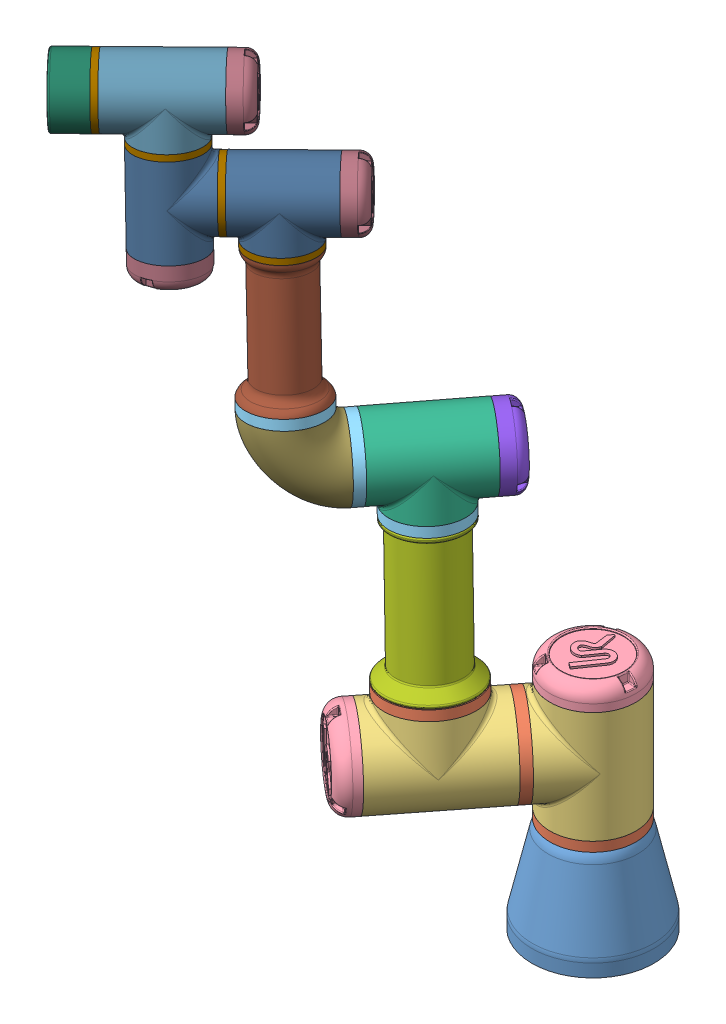
SolidWorks assembly UR3_Assembly, configuration Default. Lengths in mm.
Overall size (416.62 772.65 384.33).
31 component instances, 15 part files, 8 mates.
Components (placement in the parent):
- Base^UR3_Assembly-1: Base^UR3_Assembly [Default] at (189.025 -183.6761 -10.6435) size (133.33 250.8 135.05) (virtual)
  - Base Joint-1: Base Joint [Default] at (46.7051 9.5176 101.7932) size (128 105.8 128)
  - size 2 flange-1: size 2 flange [Default] at (46.7051 110.3176 101.7932) x (0.037243 0 -0.999306) z (0.999306 0 0.037243) size (90 10 90)
  - shoulder - base  1-1: shoulder - base  1 [Default] at (46.7051 115.3176 101.7932) x (-0.616294 0 0.787516) z (-0.787516 0 -0.616294) size (100 122 90)
  - Size 2 Cap-1: Size 2 Cap [Default] at (46.7051 237.3176 101.7932) x (-0.821952 0 -0.569557) z (0.569557 0 -0.821952) size (90 23 90)
- Arm1^UR3_Assembly-1: Arm1^UR3_Assembly [Default] at (189.025 -183.6761 -10.6435) size (169.85 344.25 189.73) (virtual)
  - size 2 flange-1: size 2 flange [Default] at (9.7275 181.3176 149.0441) x (-0.785699 0.067901 -0.614872) z (-0.053473 -0.997692 -0.041847) size (90 10 90)
  - size 2 flange-2: size 2 flange [Default] at (-31.9175 231.0523 193.9124) x (-0.996208 -0.078792 0.036901) z (-0.031709 -0.066154 -0.997305) size (90 10 90)
  - size 1 flange-1: size 1 flange [Default] at (-44.2326 382.2457 184.2748) x (0.850464 0.035819 -0.524812) z (0.519756 0.096444 0.848854) size (75 10 75)
  - size 1 flange-2: size 1 flange [Default] at (-85.0209 435.0277 228.5396) x (-0.038648 -0.998852 -0.028288) z (0.792815 -0.047883 0.607579) size (75 10 75)
  - shoulder - base  1-1: shoulder - base  1 [Default] at (12.8089 181.3176 145.1066) x (-0.081021 0.994694 -0.063405) z (0.783337 0.102881 0.613024) size (100 122 90)
  - size 1 shoulder-1: size 1 shoulder [Default] at (-81.9797 435.0225 224.5709) x (-0.081021 0.994694 -0.063405) z (-0.78961 -0.102876 -0.604923) size (85.5 105 75)
  - Upper arm-1: Upper arm [Default] at (-32.3226 236.0258 193.5953) x (-0.452157 -0.093372 -0.887038) z (0.888251 0.043199 -0.457323) size (90 152 90)
  - Size 2 Cap-1: Size 2 Cap [Default] at (-62.3789 181.3176 241.1835) x (0.787022 -0.035399 0.615908) z (-0.027877 -0.999373 -0.021816) size (90 23 90)
  - Size 1 Cap-1: Size 1 Cap [Default] at (-18.1149 434.9118 141.2265) x (-0.79161 -0.074291 -0.606494) z (0.058329 -0.997236 0.046021) size (75 23.29 75.06)
- Arm2^UR3_Assembly-1: Arm2^UR3_Assembly [Default] at (189.025 -183.6761 -10.6435) size (155.15 311.57 149.08) (virtual)
  - size 1 flange-1: size 1 flange [Default] at (-117.3097 479.6415 260.4308) x (-0.567665 0.008062 0.82322) z (-0.815973 -0.13826 -0.561314) size (75 10 75)
  - size 0  flange-1: size 0  flange [Default] at (-132.1735 614.3309 248.8621) x (-0.234714 -0.108869 -0.965949) z (0.965901 0.085606 -0.244351) size (65 6 65)
  - size 0  flange-2: size 0  flange [Default] at (-170.8519 656.3347 276.2101) x (0.414247 -0.805006 0.424694) z (0.533405 0.592805 0.603375) size (65 6 65)
  - size 0 shoulder 1-1: size 0 shoulder 1 [Default] at (-168.6395 656.405 274.1852) x (0.109293 -0.990363 0.085064) z (0.666466 0.136501 0.732933) size (73 88 65)
  - Arm 2-1: Arm 2 [Default] at (-117.8562 484.5933 260.0054) x (-0.344885 -0.118042 -0.931193) z (0.93226 0.072436 -0.354463) size (75 134 75)
  - elbow-1: elbow [Default] at (-81.9797 435.0225 224.5709) x (0.109293 -0.990363 0.085064) z (-0.786196 -0.138491 -0.602259) size (89.62 87.5 78.98)
  - Size 0 Cap-1: Size 0 Cap [Default] at (-103.7411 658.4652 214.7885) x (-0.664408 -0.154166 -0.731297) z (0.121177 -0.987768 0.098139) size (65 23.19 65.09)
- Arm3^UR3_Assembly-1: Arm3^UR3_Assembly [Default] at (189.025 -183.6761 -10.6435) size (171.69 200.45 166.27) (virtual)
  - size 0  flange-1: size 0  flange [Default] at (-204.8868 700.691 296.12) x (0.951495 0.099422 -0.291157) z (-0.274636 -0.152099 -0.949442) size (65 6 65)
  - size 0  flange-2: size 0  flange [Default] at (-246.9816 736.3905 325.4426) x (-0.112068 -0.981249 -0.156817) z (-0.665556 0.191305 -0.721413) size (65 6 65)
  - size 0 shoulder 1-1: size 0 shoulder 1 [Default] at (-204.4707 697.7409 296.4722) x (0.737481 0.023412 -0.674962) z (-0.660976 -0.180197 -0.72845) size (73 88 65)
  - size 0 shoulder 3-1: size 0 shoulder 3 [Default] at (-241.8164 736.5552 320.721) x (0.138681 -0.983352 0.117417) z (0.660524 0.180182 0.728863) size (73 98 65)
  - Tool holder-1: Tool holder [Default] at (-249.1952 736.32 327.4662) x (0.518539 -0.65947 0.544258) z (-0.43202 -0.751363 -0.498811) size (65 35 65)
  - Size 0 Cap-1: Size 0 Cap [Default] at (-192.2668 611.2059 306.8049) x (-0.650776 -0.179858 -0.737659) z (-0.746497 -0.025887 0.664885) size (65 23.19 65.09)
  - Size 0 Cap-2: Size 0 Cap [Default] at (-176.8824 738.6252 261.3636) x (-0.663714 -0.156117 -0.731513) z (0.122511 -0.987458 0.099584) size (65 23.19 65.09)
Mates (geometry in assembly coordinates):
- Coincident39: coincident anti-aligned: plane of Base^UR3 Assembly-1/shoulder - base  1-1 through (204.9154 -2.3585 130.5255) normal (-0.616294 0 0.787516); plane of Arm1^UR3 Assembly-1/size 2 flange-1 through (204.9154 -2.3585 130.5255) normal (0.616294 0 -0.787516)
- Concentric785: concentric anti-aligned: circle of Base^UR3 Assembly-1/shoulder - base  1-1; cylinder of Arm1^UR3 Assembly-1/shoulder - base  1-1 through (198.7524 -2.3585 138.4006) axis (0.616294 0 -0.787516) radius 42.5
- Coincident40: coincident anti-aligned: plane of Base^UR3 Assembly-1/shoulder - base  1-1 through (201.8339 -2.3585 134.4631) normal (-0.616294 0 0.787516); plane of Arm1^UR3 Assembly-1/shoulder - base  1-1 through (201.8339 -2.3585 134.4631) normal (0.616294 0 -0.787516)
- Concentric793: concentric anti-aligned: cylinder of Arm2^UR3 Assembly-1/elbow-1 through (104.0041 251.3517 217.8961) axis (0.608236 -0.001054 -0.793755) radius 35; cylinder of Arm1^UR3 Assembly-1/size 1 flange-2 through (110.0864 251.3411 209.9586) axis (-0.608236 0.001054 0.793755) radius 35
- Concentric794: concentric anti-aligned: cylinder of Arm2^UR3 Assembly-1/elbow-1 through (104.0041 251.3517 217.8961) axis (0.608236 -0.001054 -0.793755) radius 35; cylinder of Arm1^UR3 Assembly-1/size 1 flange-2 through (110.0864 251.3411 209.9586) axis (-0.608236 0.001054 0.793755) radius 35
- Coincident49: coincident anti-aligned: plane of Arm1^UR3 Assembly-1/size 1 shoulder-1 through (107.0452 251.3464 213.9273) normal (-0.608236 0.001054 0.793755); plane of Arm2^UR3 Assembly-1/elbow-1 through (107.0452 251.3464 213.9273) normal (0.608236 -0.001054 -0.793755)
- Concentric795: concentric aligned: cylinder of Arm2^UR3 Assembly-1/size 0  flange-2 through (22.5979 472.7991 261.5168) axis (-0.737481 -0.023412 0.674962) radius 30; cylinder of Arm3^UR3 Assembly-1/size 0 shoulder 1-1 through (20.3855 472.7289 263.5417) axis (-0.737481 -0.023412 0.674962) radius 30
- Coincident50: coincident anti-aligned: plane of Arm2^UR3 Assembly-1/size 0 shoulder 1-1 through (20.3855 472.7289 263.5417) normal (-0.737481 -0.023412 0.674962); plane of Arm3^UR3 Assembly-1/size 0 shoulder 1-1 through (20.3855 472.7289 263.5417) normal (0.737481 0.023412 -0.674962)
